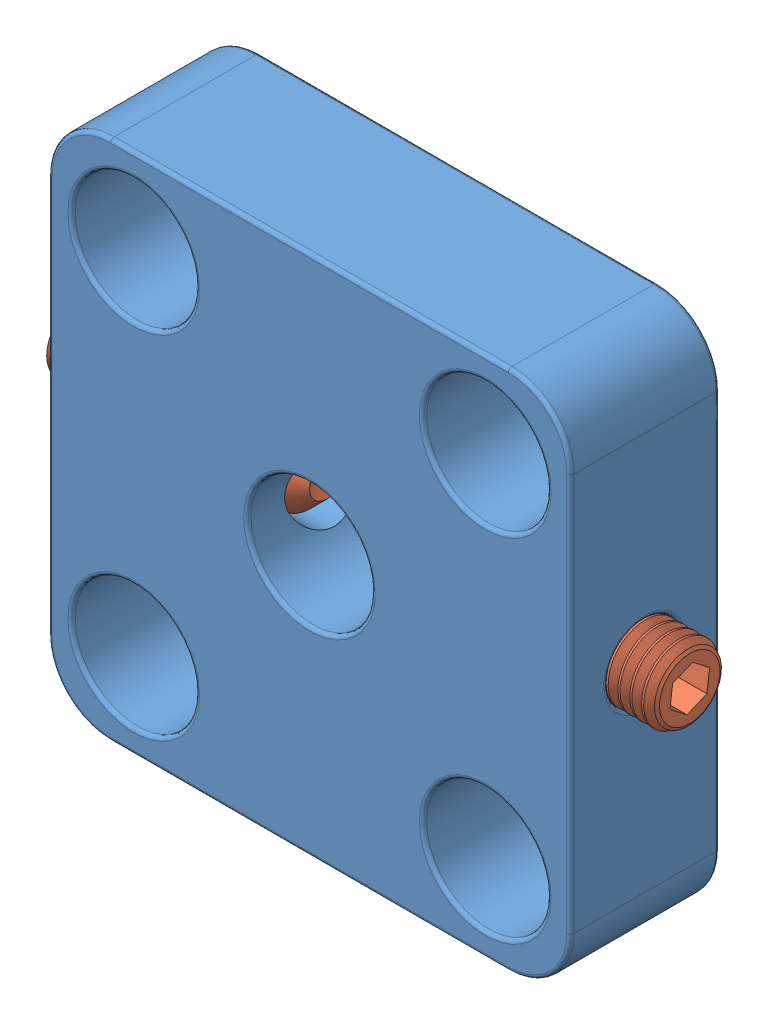
SolidWorks assembly Assem5, configuration Default. Lengths in mm.
Overall size (24.6 21 6).
3 component instances, 2 part files, 4 mates.
Components (placement in the parent):
- Mounting Hub 5mm-1: Mounting Hub 5mm [Default] at (-80.2905 -11.6322 40.5967) size (21 21 6)
- Socket Set Screw Cup Point_AM-5: Socket Set Screw Cup Point_AM [B18.3.6M - M3 x 0.5 x 10 Hex Socket Type I Cup Pt. SS --S] at (-57.4905 -1.1322 37.5967) x (-1 0 0) z (0 -0.991563 0.129626) size (10 3 3)
- Socket Set Screw Cup Point_AM-6: Socket Set Screw Cup Point_AM [B18.3.6M - M3 x 0.5 x 10 Hex Socket Type I Cup Pt. SS --S] at (-82.0905 -1.1322 37.5967) size (10 3 3)
Mates (geometry in assembly coordinates):
- Concentric3: concentric aligned: cylinder of Mounting Hub 5mm-1 through (-80.2905 -1.1322 37.5967) axis (1 0 0) radius 1.5; circle of Socket Set Screw Cup Point_AM-5
- Distance2: distance = 1.8 mm aligned: plane of Mounting Hub 5mm-1 through (-59.2905 -11.6322 34.5967) normal (1 0 0); plane of Socket Set Screw Cup Point_AM-5 through (-57.4905 -1.1322 37.5967) normal (1 0 0)
- Concentric4: concentric: cylinder of Mounting Hub 5mm-1 through (-80.2905 -1.1322 37.5967) axis (1 0 0) radius 1.5; circle of Socket Set Screw Cup Point_AM-6
- Distance4: distance = 1.8 mm aligned: plane of Socket Set Screw Cup Point_AM-6 through (-82.0905 -1.1322 37.5967) normal (-1 0 0); plane of Mounting Hub 5mm-1 through (-80.2905 -11.6322 34.5967) normal (-1 0 0)
